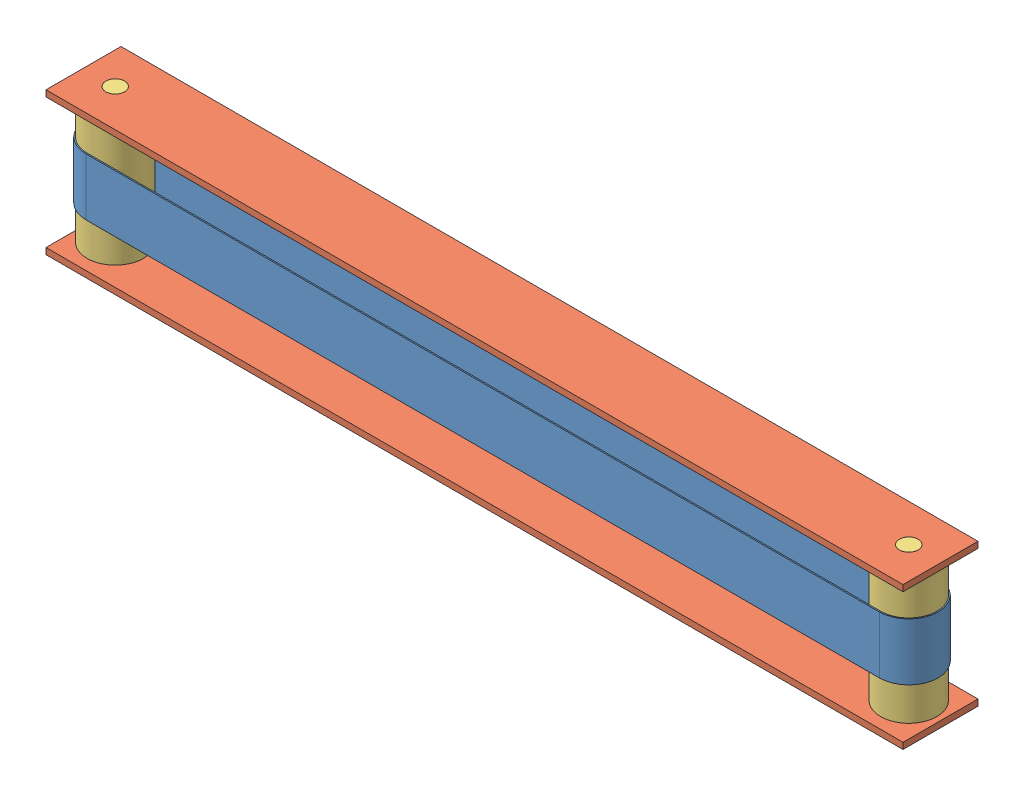
SolidWorks assembly ConveyorAssembly, configuration Default. Lengths in mm.
Overall size (685.8 114.3 60).
5 component instances, 3 part files, 8 mates.
Components (placement in the parent):
- Conveyor Belt-1: Conveyor Belt [Default] at (256.5569 496.5688 368.4002) size (682 45.72 47)
- Conveyor Stand-1: Conveyor Stand [Default] at (231.1569 572.2188 398.4002) size (685.8 5 60)
- Roller-1: Roller [Default] at (891.5569 520.0688 368.4002) size (45 114.3 45)
- Roller-2: Roller [Default] at (256.5569 520.0688 368.4002) size (45 114.3 45)
- Conveyor Stand-2: Conveyor Stand [Default] at (231.1569 462.9188 398.4002) size (685.8 5 60)
Mates (geometry in assembly coordinates):
- Concentric1: concentric aligned: cylinder of Conveyor Stand-1 through (891.5569 577.2188 368.4002) axis (0 -1 0) radius 7.5; cylinder of Roller-1 through (891.5569 577.2188 368.4002) axis (0 -1 0) radius 7.5
- Coincident1: coincident aligned: plane of Conveyor Stand-1 through (231.1569 577.2188 398.4002) normal (0 1 0); plane of Roller-1 through (891.5569 577.2188 368.4002) normal (0 1 0)
- Coincident4: coincident aligned: plane of Conveyor Stand-1 through (231.1569 577.2188 398.4002) normal (0 1 0); plane of Roller-2 through (256.5569 577.2188 368.4002) normal (0 1 0)
- Concentric3: concentric aligned: cylinder of Conveyor Stand-1 through (256.5569 577.2188 368.4002) axis (0 -1 0) radius 7.5; cylinder of Roller-2 through (256.5569 577.2188 368.4002) axis (0 -1 0) radius 7.5
- Distance1: distance = 27.3 mm aligned: plane of Conveyor Belt-1 through (256.5569 496.5688 368.4002) normal (0 -1 0); plane of Roller-1 through (891.5569 469.2688 368.4002) normal (0 -1 0)
- Concentric4: concentric: cylinder of assembly; point of Conveyor Belt-1; cylinder of Roller-1 through (891.5569 577.2188 368.4002) axis (0 -1 0) radius 7.5
- Concentric5: concentric aligned: cylinder of Roller-1 through (891.5569 577.2188 368.4002) axis (0 -1 0) radius 7.5; cylinder of Conveyor Stand-2 through (891.5569 467.9188 368.4002) axis (0 -1 0) radius 7.5
- Coincident7: coincident aligned: plane of Roller-1 through (891.5569 462.9188 368.4002) normal (0 -1 0); plane of Conveyor Stand-2 through (231.1569 462.9188 398.4002) normal (0 -1 0)
